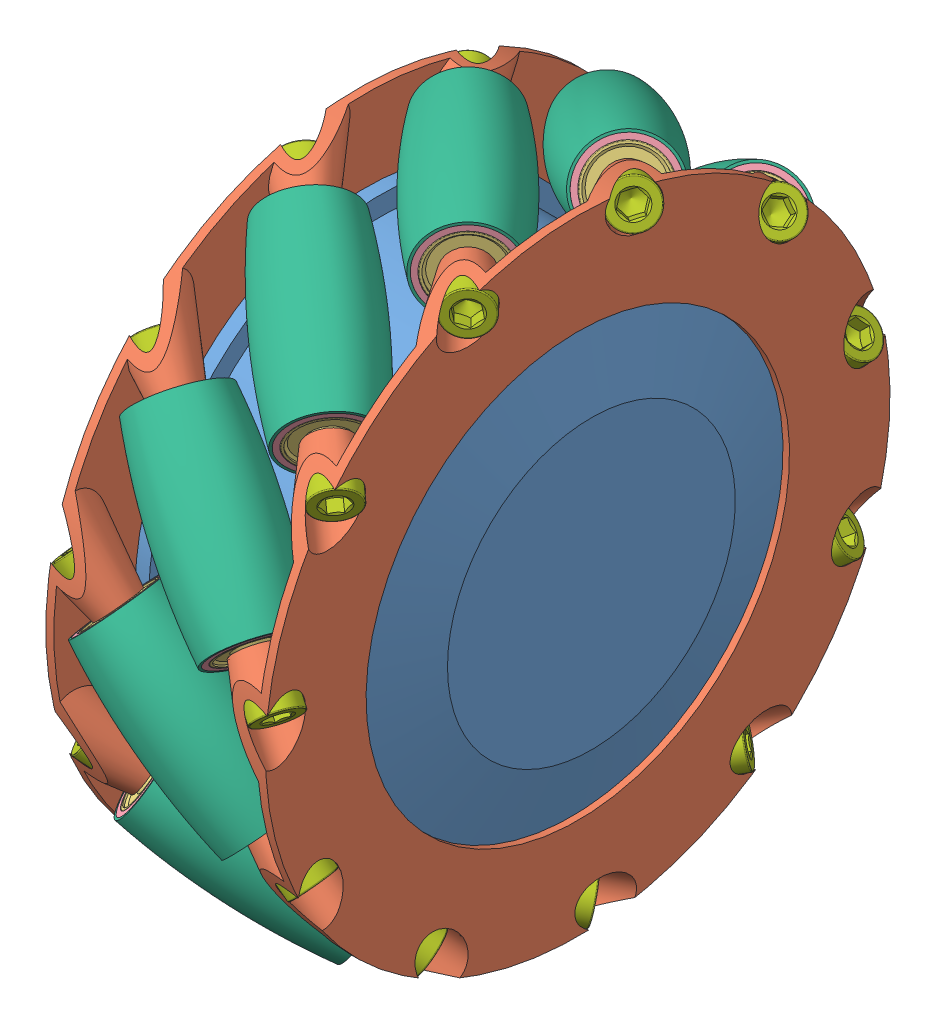
SolidWorks assembly ТП.SH21(К4).02.00 -Колесо А, configuration 00. Lengths in mm.
Overall size (133.84 317.84 317.84).
102 component instances, 8 part files, 10 mates.
Components (placement in the parent):
- Мотор-колесо ZLLG80ASM800 (мотор)-1: Мотор-колесо ZLLG80ASM800 (мотор) [1 крепление] at origin size (133 170 170)
- ТП.SH21(К4).01.01 - Фланец колеса-1: ТП.SH21(К4).01.01 - Фланец колеса [--] at (-37.5 0 0) x (0 0 -1) z (1 0 0) size (230 230 22.27)
- ТП.SH21(К4).01.02.00 - Ролик диагональный-1: ТП.SH21(К4).01.02.00 - Ролик диагональный [00] at (0 85.3872 54.875) x (0.234129 -0.667221 -0.707107) z (-0.707107 0.382291 -0.594856) size (37 37 69.98)
  - Боченок габарит-1: Боченок габарит [--] at origin size (37 37 91.92) (hidden)
  - Подшипник 6100-1: Подшипник 6100 [--] at (0 0 30.99) x (0 0 1) z (0.161819 -0.986821 0) size (8 26 26)
  - ТП.SH21(К4).01.02.01 - Ступица-1: ТП.SH21(К4).01.02.01 - Ступица [--] at origin size (30 30 69.98)
  - ТП.SH21(К4).01.02.02 - Ось-1: ТП.SH21(К4).01.02.02 - Ось [--] at origin size (14 14 53.98)
  - Подшипник 6100-2: Подшипник 6100 [--] at (0 0 -30.99) x (0 0 -1) z (-0.273874 0.961766 0) size (8 26 26)
  - ТП.SH21(К4).01.02.03 - Покрышка-1: ТП.SH21(К4).01.02.03 - Покрышка [--] at origin size (37 37 69.98)
- ТП.SH21(К4).01.02.00 - Ролик диагональный-2: ТП.SH21(К4).01.02.00 - Ролик диагональный [00] at (0 101.5 0) x (0.234129 -0.943593 -0.234129) z (-0.707107 0 -0.707107) size (37 37 69.98)
  - Боченок габарит-1: Боченок габарит [--] at origin size (37 37 91.92) (hidden)
  - Подшипник 6100-1: Подшипник 6100 [--] at (0 0 30.99) x (0 0 1) z (0.161819 -0.986821 0) size (8 26 26)
  - ТП.SH21(К4).01.02.01 - Ступица-1: ТП.SH21(К4).01.02.01 - Ступица [--] at origin size (30 30 69.98)
  - ТП.SH21(К4).01.02.02 - Ось-1: ТП.SH21(К4).01.02.02 - Ось [--] at origin size (14 14 53.98)
  - Подшипник 6100-2: Подшипник 6100 [--] at (0 0 -30.99) x (0 0 -1) z (-0.273874 0.961766 0) size (8 26 26)
  - ТП.SH21(К4).01.02.03 - Покрышка-1: ТП.SH21(К4).01.02.03 - Покрышка [--] at origin size (37 37 69.98)
- ТП.SH21(К4).01.02.00 - Ролик диагональный-3: ТП.SH21(К4).01.02.00 - Ролик диагональный [00] at (0 85.3872 -54.875) x (0.234129 -0.92038 0.313183) z (-0.707107 -0.382291 -0.594856) size (37 37 69.98)
  - Боченок габарит-1: Боченок габарит [--] at origin size (37 37 91.92) (hidden)
  - Подшипник 6100-1: Подшипник 6100 [--] at (0 0 30.99) x (0 0 1) z (0.161819 -0.986821 0) size (8 26 26)
  - ТП.SH21(К4).01.02.01 - Ступица-1: ТП.SH21(К4).01.02.01 - Ступица [--] at origin size (30 30 69.98)
  - ТП.SH21(К4).01.02.02 - Ось-1: ТП.SH21(К4).01.02.02 - Ось [--] at origin size (14 14 53.98)
  - Подшипник 6100-2: Подшипник 6100 [--] at (0 0 -30.99) x (0 0 -1) z (-0.273874 0.961766 0) size (8 26 26)
  - ТП.SH21(К4).01.02.03 - Покрышка-1: ТП.SH21(К4).01.02.03 - Покрышка [--] at origin size (37 37 69.98)
- ТП.SH21(К4).01.02.00 - Ролик диагональный-4: ТП.SH21(К4).01.02.00 - Ролик диагональный [00] at (0 42.1646 -92.3276) x (0.234129 -0.604954 0.761061) z (-0.707107 -0.643207 -0.293743) size (37 37 69.98)
  - Боченок габарит-1: Боченок габарит [--] at origin size (37 37 91.92) (hidden)
  - Подшипник 6100-1: Подшипник 6100 [--] at (0 0 30.99) x (0 0 1) z (0.161819 -0.986821 0) size (8 26 26)
  - ТП.SH21(К4).01.02.01 - Ступица-1: ТП.SH21(К4).01.02.01 - Ступица [--] at origin size (30 30 69.98)
  - ТП.SH21(К4).01.02.02 - Ось-1: ТП.SH21(К4).01.02.02 - Ось [--] at origin size (14 14 53.98)
  - Подшипник 6100-2: Подшипник 6100 [--] at (0 0 -30.99) x (0 0 -1) z (-0.273874 0.961766 0) size (8 26 26)
  - ТП.SH21(К4).01.02.03 - Покрышка-1: ТП.SH21(К4).01.02.03 - Покрышка [--] at origin size (37 37 69.98)
- ТП.SH21(К4).01.02.00 - Ролик диагональный-5: ТП.SH21(К4).01.02.00 - Ролик диагональный [00] at (0 -14.445 -100.4669) x (0.234129 -0.097459 0.967308) z (-0.707107 -0.699909 0.100632) size (37 37 69.98)
  - Боченок габарит-1: Боченок габарит [--] at origin size (37 37 91.92) (hidden)
  - Подшипник 6100-1: Подшипник 6100 [--] at (0 0 30.99) x (0 0 1) z (0.161819 -0.986821 0) size (8 26 26)
  - ТП.SH21(К4).01.02.01 - Ступица-1: ТП.SH21(К4).01.02.01 - Ступица [--] at origin size (30 30 69.98)
  - ТП.SH21(К4).01.02.02 - Ось-1: ТП.SH21(К4).01.02.02 - Ось [--] at origin size (14 14 53.98)
  - Подшипник 6100-2: Подшипник 6100 [--] at (0 0 -30.99) x (0 0 -1) z (-0.273874 0.961766 0) size (8 26 26)
  - ТП.SH21(К4).01.02.03 - Покрышка-1: ТП.SH21(К4).01.02.03 - Покрышка [--] at origin size (37 37 69.98)
- ТП.SH21(К4).01.02.00 - Ролик диагональный-6: ТП.SH21(К4).01.02.00 - Ролик диагональный [00] at (0 -66.4684 -76.7086) x (0.234129 0.440979 0.866442) z (-0.707107 -0.534396 0.463056) size (37 37 69.98)
  - Боченок габарит-1: Боченок габарит [--] at origin size (37 37 91.92) (hidden)
  - Подшипник 6100-1: Подшипник 6100 [--] at (0 0 30.99) x (0 0 1) z (0.161819 -0.986821 0) size (8 26 26)
  - ТП.SH21(К4).01.02.01 - Ступица-1: ТП.SH21(К4).01.02.01 - Ступица [--] at origin size (30 30 69.98)
  - ТП.SH21(К4).01.02.02 - Ось-1: ТП.SH21(К4).01.02.02 - Ось [--] at origin size (14 14 53.98)
  - Подшипник 6100-2: Подшипник 6100 [--] at (0 0 -30.99) x (0 0 -1) z (-0.273874 0.961766 0) size (8 26 26)
  - ТП.SH21(К4).01.02.03 - Покрышка-1: ТП.SH21(К4).01.02.03 - Покрышка [--] at origin size (37 37 69.98)
- ТП.SH21(К4).01.02.00 - Ролик диагональный-7: ТП.SH21(К4).01.02.00 - Ролик диагональный [00] at (0 -97.3885 -28.5959) x (0.234129 0.839409 0.490486) z (-0.707107 -0.199215 0.678464) size (37 37 69.98)
  - Боченок габарит-1: Боченок габарит [--] at origin size (37 37 91.92) (hidden)
  - Подшипник 6100-1: Подшипник 6100 [--] at (0 0 30.99) x (0 0 1) z (0.161819 -0.986821 0) size (8 26 26)
  - ТП.SH21(К4).01.02.01 - Ступица-1: ТП.SH21(К4).01.02.01 - Ступица [--] at origin size (30 30 69.98)
  - ТП.SH21(К4).01.02.02 - Ось-1: ТП.SH21(К4).01.02.02 - Ось [--] at origin size (14 14 53.98)
  - Подшипник 6100-2: Подшипник 6100 [--] at (0 0 -30.99) x (0 0 -1) z (-0.273874 0.961766 0) size (8 26 26)
  - ТП.SH21(К4).01.02.03 - Покрышка-1: ТП.SH21(К4).01.02.03 - Покрышка [--] at origin size (37 37 69.98)
- ТП.SH21(К4).01.02.00 - Ролик диагональный-8: ТП.SH21(К4).01.02.00 - Ролик диагональный [00] at (0 -97.3885 28.5959) x (0.234129 0.971332 -0.041195) z (-0.707107 0.199215 0.678464) size (37 37 69.98)
  - Боченок габарит-1: Боченок габарит [--] at origin size (37 37 91.92) (hidden)
  - Подшипник 6100-1: Подшипник 6100 [--] at (0 0 30.99) x (0 0 1) z (0.161819 -0.986821 0) size (8 26 26)
  - ТП.SH21(К4).01.02.01 - Ступица-1: ТП.SH21(К4).01.02.01 - Ступица [--] at origin size (30 30 69.98)
  - ТП.SH21(К4).01.02.02 - Ось-1: ТП.SH21(К4).01.02.02 - Ось [--] at origin size (14 14 53.98)
  - Подшипник 6100-2: Подшипник 6100 [--] at (0 0 -30.99) x (0 0 -1) z (-0.273874 0.961766 0) size (8 26 26)
  - ТП.SH21(К4).01.02.03 - Покрышка-1: ТП.SH21(К4).01.02.03 - Покрышка [--] at origin size (37 37 69.98)
- ТП.SH21(К4).01.02.00 - Ролик диагональный-9: ТП.SH21(К4).01.02.00 - Ролик диагональный [00] at (0 -66.4684 76.7086) x (0.234129 0.794865 -0.559798) z (-0.707107 0.534396 0.463056) size (37 37 69.98)
  - Боченок габарит-1: Боченок габарит [--] at origin size (37 37 91.92) (hidden)
  - Подшипник 6100-1: Подшипник 6100 [--] at (0 0 30.99) x (0 0 1) z (0.161819 -0.986821 0) size (8 26 26)
  - ТП.SH21(К4).01.02.01 - Ступица-1: ТП.SH21(К4).01.02.01 - Ступица [--] at origin size (30 30 69.98)
  - ТП.SH21(К4).01.02.02 - Ось-1: ТП.SH21(К4).01.02.02 - Ось [--] at origin size (14 14 53.98)
  - Подшипник 6100-2: Подшипник 6100 [--] at (0 0 -30.99) x (0 0 -1) z (-0.273874 0.961766 0) size (8 26 26)
  - ТП.SH21(К4).01.02.03 - Покрышка-1: ТП.SH21(К4).01.02.03 - Покрышка [--] at origin size (37 37 69.98)
- ТП.SH21(К4).01.02.00 - Ролик диагональный-10: ТП.SH21(К4).01.02.00 - Ролик диагональный [00] at (0 -14.445 100.4669) x (0.234129 0.366033 -0.900668) z (-0.707107 0.699909 0.100632) size (37 37 69.98)
  - Боченок габарит-1: Боченок габарит [--] at origin size (37 37 91.92) (hidden)
  - Подшипник 6100-1: Подшипник 6100 [--] at (0 0 30.99) x (0 0 1) z (0.161819 -0.986821 0) size (8 26 26)
  - ТП.SH21(К4).01.02.01 - Ступица-1: ТП.SH21(К4).01.02.01 - Ступица [--] at origin size (30 30 69.98)
  - ТП.SH21(К4).01.02.02 - Ось-1: ТП.SH21(К4).01.02.02 - Ось [--] at origin size (14 14 53.98)
  - Подшипник 6100-2: Подшипник 6100 [--] at (0 0 -30.99) x (0 0 -1) z (-0.273874 0.961766 0) size (8 26 26)
  - ТП.SH21(К4).01.02.03 - Покрышка-1: ТП.SH21(К4).01.02.03 - Покрышка [--] at origin size (37 37 69.98)
- ТП.SH21(К4).01.02.00 - Ролик диагональный-11: ТП.SH21(К4).01.02.00 - Ролик диагональный [00] at (0 42.1646 92.3276) x (0.234129 -0.179011 -0.955583) z (-0.707107 0.643207 -0.293743) size (37 37 69.98)
  - Боченок габарит-1: Боченок габарит [--] at origin size (37 37 91.92) (hidden)
  - Подшипник 6100-1: Подшипник 6100 [--] at (0 0 30.99) x (0 0 1) z (0.161819 -0.986821 0) size (8 26 26)
  - ТП.SH21(К4).01.02.01 - Ступица-1: ТП.SH21(К4).01.02.01 - Ступица [--] at origin size (30 30 69.98)
  - ТП.SH21(К4).01.02.02 - Ось-1: ТП.SH21(К4).01.02.02 - Ось [--] at origin size (14 14 53.98)
  - Подшипник 6100-2: Подшипник 6100 [--] at (0 0 -30.99) x (0 0 -1) z (-0.273874 0.961766 0) size (8 26 26)
  - ТП.SH21(К4).01.02.03 - Покрышка-1: ТП.SH21(К4).01.02.03 - Покрышка [--] at origin size (37 37 69.98)
- Винты с цилиндрической головкой (ГОСТ 11738-84)-2: Винты с цилиндрической головкой (ГОСТ 11738-84) [Винт М10-(6g)x35 ГОСТ 11738-84] at (-31.1056 102.2042 28.7073) x (-0.23283 -0.920219 -0.314623) z (-0.707107 0.382291 -0.594856) size (16 16 45.28)
- Винты с цилиндрической головкой (ГОСТ 11738-84)-3: Винты с цилиндрической головкой (ГОСТ 11738-84) [Винт М10-(6g)x35 ГОСТ 11738-84] at (-31.1056 101.5 -31.1056) x (-0.23283 -0.944235 0.23283) z (-0.707107 0 -0.707107) size (16 16 45.28)
- Винты с цилиндрической головкой (ГОСТ 11738-84)-4: Винты с цилиндрической головкой (ГОСТ 11738-84) [Винт М10-(6g)x35 ГОСТ 11738-84] at (-31.1056 68.5703 -81.0428) x (-0.23283 -0.668464 0.706361) z (-0.707107 -0.382291 -0.594856) size (16 16 45.28)
- Винты с цилиндрической головкой (ГОСТ 11738-84)-5: Винты с цилиндрической головкой (ГОСТ 11738-84) [Винт М10-(6g)x35 ГОСТ 11738-84] at (-31.1056 13.8699 -105.2494) x (-0.23283 -0.18046 0.955628) z (-0.707107 -0.643207 -0.293743) size (16 16 45.28)
- Винты с цилиндрической головкой (ГОСТ 11738-84)-6: Винты с цилиндрической головкой (ГОСТ 11738-84) [Винт М10-(6g)x35 ГОСТ 11738-84] at (-31.1056 -45.234 -96.0401) x (-0.23283 0.364839 0.901489) z (-0.707107 -0.699909 0.100632) size (16 16 45.28)
- Винты с цилиндрической головкой (ГОСТ 11738-84)-7: Винты с цилиндрической головкой (ГОСТ 11738-84) [Винт М10-(6g)x35 ГОСТ 11738-84] at (-31.1056 -89.9764 -56.3387) x (-0.23283 0.794304 0.561134) z (-0.707107 -0.534396 0.463056) size (16 16 45.28)
- Винты с цилиндрической головкой (ГОСТ 11738-84)-8: Винты с цилиндрической головкой (ГОСТ 11738-84) [Винт М10-(6g)x35 ГОСТ 11738-84] at (-31.1056 -106.152 1.2498) x (-0.23283 0.971583 0.042623) z (-0.707107 -0.199215 0.678464) size (16 16 45.28)
- Винты с цилиндрической головкой (ГОСТ 11738-84)-9: Винты с цилиндрической головкой (ГОСТ 11738-84) [Винт М10-(6g)x35 ГОСТ 11738-84] at (-31.1056 -88.6251 58.4415) x (-0.23283 0.840391 -0.489421) z (-0.707107 0.199215 0.678464) size (16 16 45.28)
- Винты с цилиндрической головкой (ГОСТ 11738-84)-10: Винты с цилиндрической головкой (ГОСТ 11738-84) [Винт М10-(6g)x35 ГОСТ 11738-84] at (-31.1056 -42.9603 97.0784) x (-0.23283 0.442382 -0.866077) z (-0.707107 0.534396 0.463056) size (16 16 45.28)
- Винты с цилиндрической головкой (ГОСТ 11738-84)-11: Винты с цилиндрической головкой (ГОСТ 11738-84) [Винт М10-(6g)x35 ГОСТ 11738-84] at (-31.1056 16.3441 104.8937) x (-0.23283 -0.096081 -0.96776) z (-0.707107 0.699909 0.100632) size (16 16 45.28)
- Винты с цилиндрической головкой (ГОСТ 11738-84)-12: Винты с цилиндрической головкой (ГОСТ 11738-84) [Винт М10-(6g)x35 ГОСТ 11738-84] at (-31.1056 70.4593 79.4059) x (-0.23283 -0.604039 -0.762186) z (-0.707107 0.643207 -0.293743) size (16 16 45.28)
- ТП.SH21(К4).01.01 - Фланец колеса-2: ТП.SH21(К4).01.01 - Фланец колеса [--] at (37.5 0 0) x (0 0.540641 0.841254) z (-1 0 0) size (230 230 22.27)
- Винты с цилиндрической головкой (ГОСТ 11738-84)-13: Винты с цилиндрической головкой (ГОСТ 11738-84) [Винт М10-(6g)x35 ГОСТ 11738-84] at (31.1056 101.5 31.1056) x (0.449434 -0.772023 -0.449434) z (0.707107 0 0.707107) size (16 16 45.28)
- Винты с цилиндрической головкой (ГОСТ 11738-84)-14: Винты с цилиндрической головкой (ГОСТ 11738-84) [Винт М10-(6g)x35 ГОСТ 11738-84] at (31.1056 102.2042 -28.7073) x (0.449434 -0.892449 0.039299) z (0.707107 0.382291 0.594856) size (16 16 45.28)
- Винты с цилиндрической головкой (ГОСТ 11738-84)-15: Винты с цилиндрической головкой (ГОСТ 11738-84) [Винт М10-(6g)x35 ГОСТ 11738-84] at (31.1056 70.4593 -79.4059) x (0.449434 -0.729529 0.515555) z (0.707107 0.643207 0.293743) size (16 16 45.28)
- Винты с цилиндрической головкой (ГОСТ 11738-84)-16: Винты с цилиндрической головкой (ГОСТ 11738-84) [Винт М10-(6g)x35 ГОСТ 11738-84] at (31.1056 16.3441 -104.8937) x (0.449434 -0.334989 0.828126) z (0.707107 0.699909 -0.100632) size (16 16 45.28)
- Винты с цилиндрической головкой (ГОСТ 11738-84)-17: Винты с цилиндрической головкой (ГОСТ 11738-84) [Винт М10-(6g)x35 ГОСТ 11738-84] at (31.1056 -42.9603 -97.0784) x (0.449434 0.165908 0.877772) z (0.707107 0.534396 -0.463056) size (16 16 45.28)
- Винты с цилиндрической головкой (ГОСТ 11738-84)-18: Винты с цилиндрической головкой (ГОСТ 11738-84) [Винт М10-(6g)x35 ГОСТ 11738-84] at (31.1056 -88.6251 -58.4415) x (0.449434 0.61413 0.648732) z (0.707107 0.199215 -0.678464) size (16 16 45.28)
- Винты с цилиндрической головкой (ГОСТ 11738-84)-19: Винты с цилиндрической головкой (ГОСТ 11738-84) [Винт М10-(6g)x35 ГОСТ 11738-84] at (31.1056 -106.152 -1.2498) x (0.449434 0.86737 0.213724) z (0.707107 -0.199215 -0.678464) size (16 16 45.28)
- Винты с цилиндрической головкой (ГОСТ 11738-84)-20: Винты с цилиндрической головкой (ГОСТ 11738-84) [Винт М10-(6g)x35 ГОСТ 11738-84] at (31.1056 -89.9764 56.3387) x (0.449434 0.845227 -0.289139) z (0.707107 -0.534396 -0.463056) size (16 16 45.28)
- Винты с цилиндрической головкой (ГОСТ 11738-84)-21: Винты с цилиндрической головкой (ГОСТ 11738-84) [Винт М10-(6g)x35 ГОСТ 11738-84] at (31.1056 -45.234 96.0401) x (0.449434 0.554729 -0.700204) z (0.707107 -0.699909 -0.100632) size (16 16 45.28)
- Винты с цилиндрической головкой (ГОСТ 11738-84)-22: Винты с цилиндрической головкой (ГОСТ 11738-84) [Винт М10-(6g)x35 ГОСТ 11738-84] at (31.1056 13.8699 105.2494) x (0.449434 0.088109 -0.888958) z (0.707107 -0.643207 0.293743) size (16 16 45.28)
- Винты с цилиндрической головкой (ГОСТ 11738-84)-23: Винты с цилиндрической головкой (ГОСТ 11738-84) [Винт М10-(6g)x35 ГОСТ 11738-84] at (31.1056 68.5703 81.0428) x (0.449434 -0.406485 -0.795475) z (0.707107 -0.382291 0.594856) size (16 16 45.28)
Mates (geometry in assembly coordinates):
- Совпадение1: coincident: plane of Мотор-колесо ZLLG80ASM800 (мотор)-1 through (-37.5 85 0) normal (-1 0 0); plane of ТП.SH21(К4).01.01 - Фланец колеса-1 through (-37.5 0 0) normal (1 0 0)
- Концентричный1: concentric: circle of Мотор-колесо ZLLG80ASM800 (мотор)-1; cylinder of ТП.SH21(К4).01.01 - Фланец колеса-1 through (-40.5 0 0) axis (1 0 0) radius 78
- Концентричный2: concentric: cylinder of ТП.SH21(К4).01.01 - Фланец колеса-1 through (-6.3569 88.824 49.5273) axis (0.707107 -0.382291 0.594856) radius 5; cylinder of ТП.SH21(К4).01.02.00 - Ролик диагональный-1/Подшипник 6100-1 through (685.1935 -285.0564 631.2965) axis (0.707107 -0.382291 0.594856) radius 5
- Совпадение2: coincident: plane of ТП.SH21(К4).01.01 - Фланец колеса-1 through (-24.7417 98.7636 34.061) normal (0.707107 -0.382291 0.594856); plane of ТП.SH21(К4).01.02.00 - Ролик диагональный-1/Подшипник 6100-1 through (-25.4801 103.3348 37.8766) normal (-0.707107 0.382291 -0.594856)
- Концентричный3: concentric: cylinder of ТП.SH21(К4).01.02.00 - Ролик диагональный-1/Подшипник 6100-1 through (685.1935 -285.0564 631.2965) axis (0.707107 -0.382291 0.594856) radius 5; cylinder of Винты с цилиндрической головкой (ГОСТ 11738-84)-2 through (-6.3569 88.824 49.5273) axis (0.707107 -0.382291 0.594856) radius 5
- Совпадение3: coincident: plane of ТП.SH21(К4).01.01 - Фланец колеса-1 through (-31.1056 102.2042 28.7073) normal (-0.707107 0.382291 -0.594856); plane of Винты с цилиндрической головкой (ГОСТ 11738-84)-2 through (-34.8446 101.734 32.8496) normal (0.707107 -0.382291 0.594856)
- Концентричный6: concentric: cylinder of ТП.SH21(К4).01.02.00 - Ролик диагональный-1/Подшипник 6100-2 through (-685.1935 455.8308 -521.5464) axis (-0.707107 0.382291 -0.594856) radius 5; cylinder of ТП.SH21(К4).01.01 - Фланец колеса-2 through (6.3569 81.9504 60.2228) axis (-0.707107 0.382291 -0.594856) radius 5
- Совпадение5: coincident: plane of Мотор-колесо ZLLG80ASM800 (мотор)-1 through (37.5 85 0) normal (1 0 0); plane of ТП.SH21(К4).01.01 - Фланец колеса-2 through (37.5 0 0) normal (-1 0 0)
- Концентричный7: concentric: cylinder of ТП.SH21(К4).01.01 - Фланец колеса-2 through (6.3569 101.5 6.3569) axis (-0.707107 0 -0.707107) radius 5; cylinder of Винты с цилиндрической головкой (ГОСТ 11738-84)-13 through (6.3569 101.5 6.3569) axis (-0.707107 0 -0.707107) radius 5
- Совпадение6: coincident: plane of ТП.SH21(К4).01.01 - Фланец колеса-2 through (31.1056 101.5 31.1056) normal (0.707107 0 0.707107); plane of Винты с цилиндрической головкой (ГОСТ 11738-84)-13 through (34.1627 105.0593 28.0486) normal (-0.707107 0 -0.707107)
